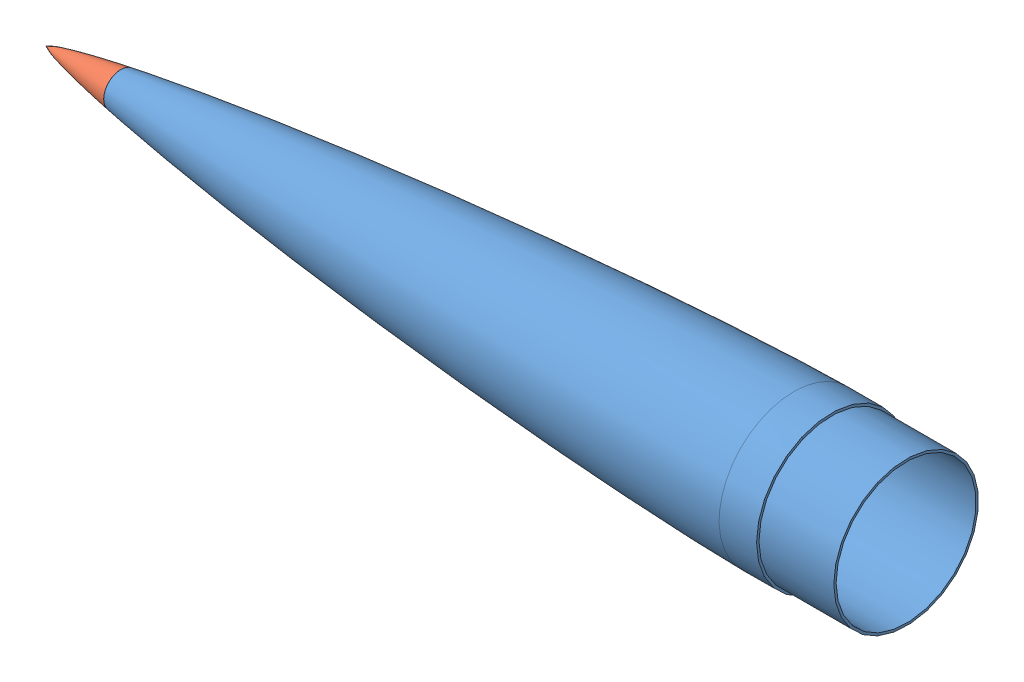
SolidWorks assembly Nose Cone, configuration Default. Lengths in mm.
Overall size (1168.4 203.32 203.2).
3 component instances, 3 part files, 3 mates.
Components (placement in the parent):
- 14001-01-NOSE_CONE_MAIN_PORTION-1: 14001-01-NOSE_CONE_MAIN_PORTION [Default] at (-20.5327 457.9409 932.6752) size (1168.4 203.2 203.2)
- 14001-01-NOSE_CONE_METAL_TIP-1: 14001-01-NOSE_CONE_METAL_TIP [Default] at (-20.0444 458.0561 932.6752) size (1016.49 124.93 46.42)
- 14001-01-NOSE_CONE_TABS-1: 14001-01-NOSE_CONE_TABS [Default] at (-20.5327 457.9409 932.6752) size (14.85 196.59 196.59)
Mates (geometry in assembly coordinates):
- Concentric1: concentric: circle of 14001-01-NOSE_CONE_MAIN_PORTION-1; circle of 14001-01-NOSE_CONE_METAL_TIP-1
- Coincident1: coincident: plane of 14001-01-NOSE_CONE_MAIN_PORTION-1 through (81.0673 481.1195 932.6752) normal (-1 0 0); plane of 14001-01-NOSE_CONE_METAL_TIP-1 through (81.0673 463.0209 932.6752) normal (1 0 0)
- Coincident2: coincident: circle of 14001-01-NOSE_CONE_MAIN_PORTION-1; circle of 14001-01-NOSE_CONE_TABS-1
